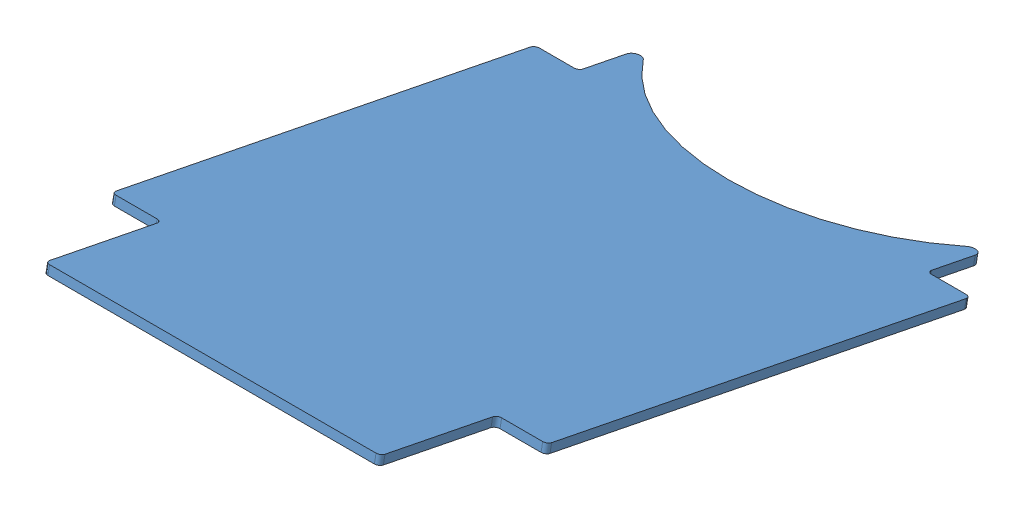
SolidWorks assembly GE-22331, configuration Default. Lengths in mm.
Overall size (317.5 92.46 434.74).
3 component instances, 2 part files, 9 mates.
Components (placement in the parent):
- GE-22330-1: GE-22330 [Default] at origin size (317.5 92.46 434.74)
- Loop_1_9-1: Loop_1_9 [Default] at (3.175 50.7252 104.1575) x (0 0.19509 0.980785) z (-1 0 0) size (228.6 1.59 25.4)
- Loop_1_9-2: Loop_1_9 [Default] at (314.325 95.3229 328.365) x (0 -0.19509 -0.980785) z (1 0 0) size (228.6 1.59 25.4)
Mates (geometry in assembly coordinates):
- Coincident1: coincident anti-aligned: plane of GE-22330-1 through (317.5 31.872 1.2388) normal (0 -0.980785 0.19509); plane of Loop_1_9-1 through (3.175 52.2822 103.8478) normal (0 0.980785 -0.19509)
- Distance2: distance = 3.175 mm aligned: plane of GE-22330-1 through (0 0 0) normal (-1 0 0); plane of Loop_1_9-1 through (3.175 52.2822 103.8478) normal (-1 0 0)
- Distance1: distance = 52.07 mm aligned: plane of GE-22330-1 through (0 25.6319 395.3176) normal (0 0.19509 0.980785); plane of Loop_1_9-1 through (3.175 96.8799 328.0553) normal (0 0.19509 0.980785)
- Coincident3: coincident anti-aligned: plane of GE-22330-1 through (317.5 31.872 1.2388) normal (0 -0.980785 0.19509); plane of Loop_1_9-2 through (314.325 96.8799 328.0553) normal (0 0.980785 -0.19509)
- Coincident4: coincident aligned: plane of Loop_1_9-1 through (3.175 96.8799 328.0553) normal (0 0.19509 0.980785); plane of Loop_1_9-2 through (314.325 96.8799 328.0553) normal (0 0.19509 0.980785)
- Distance3: distance = 3.175 mm aligned: plane of GE-22330-1 through (317.5 0 0) normal (1 0 0); plane of Loop_1_9-2 through (314.325 96.8799 328.0553) normal (1 0 0)
- Coincident6: coincident aligned: plane of GE-22330-1 through (0 0 0) normal (0 0 1)
- Coincident7: coincident aligned: plane of GE-22330-1 through (0 0 0) normal (0 1 0)
- Coincident8: coincident aligned: plane of GE-22330-1 through (0 0 0) normal (1 0 0)
